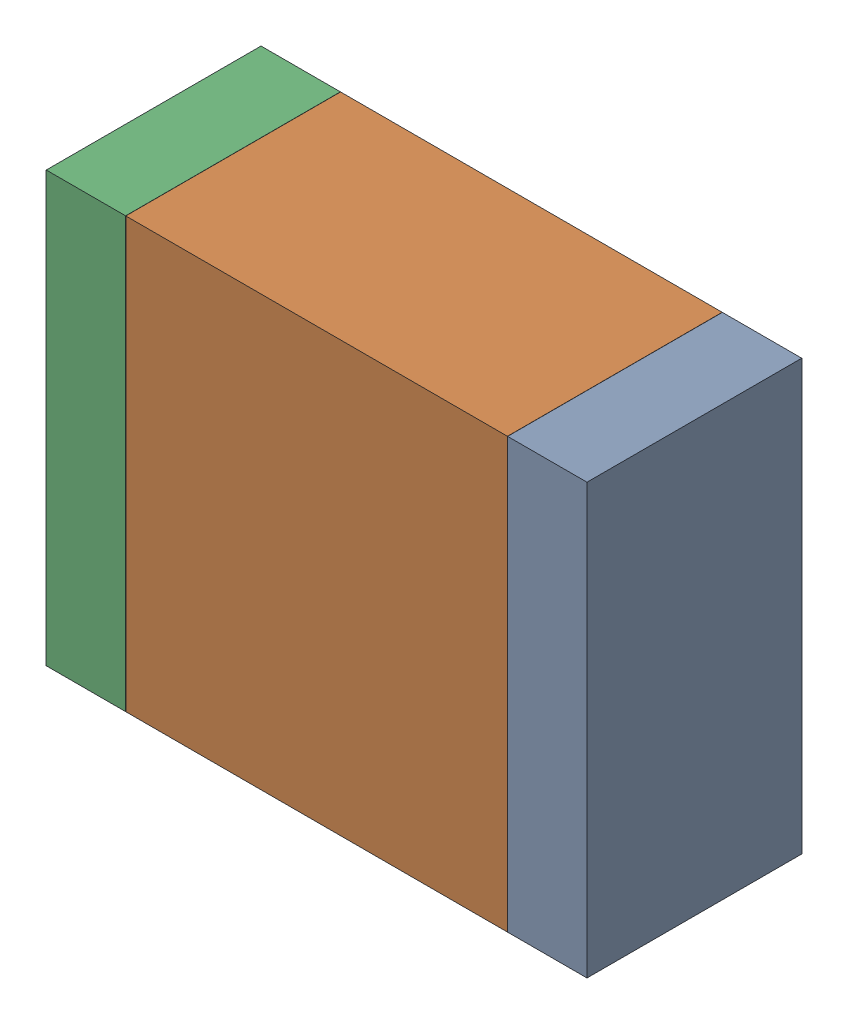
SolidWorks assembly C20, configuration Default. Lengths in mm.
Overall size (3.4 2.7 1.35).
6 component instances, 2 part files, 0 mates.
Components (placement in the parent):
- 6575498672-1: 6575498672 [Default] at (35.486 15.24 0) size (0.5 2.7 1.35)
  - Extruded_18-1: Extruded_18 [Default] at origin size (0.5 2.7 1.35)
- 6575498512-1: 6575498512 [Default] at (34.036 15.24 0) size (2.4 2.7 1.35)
  - Extruded_19-1: Extruded_19 [Default] at origin size (2.4 2.7 1.35)
- 6575498672-2: 6575498672 [Default] at (32.586 15.24 0) size (0.5 2.7 1.35)
  - Extruded_18-1: Extruded_18 [Default] at origin size (0.5 2.7 1.35)
